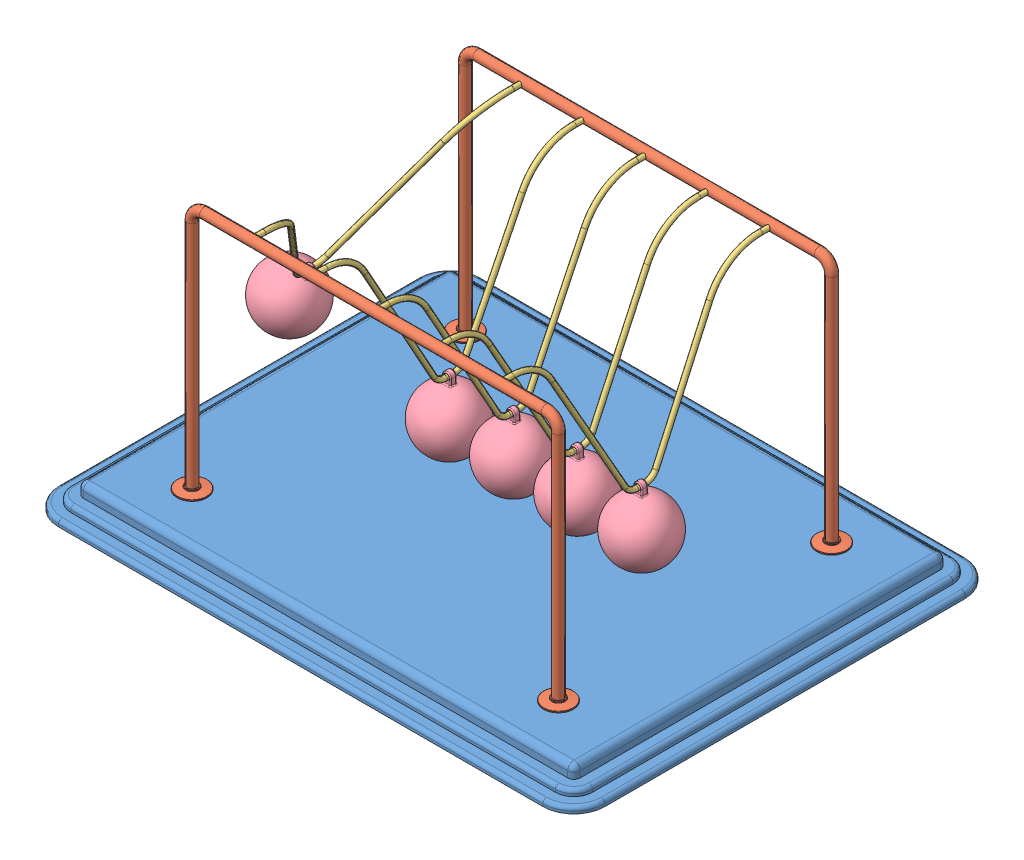
SolidWorks assembly Newtons Cradle NewtonsCradle 0237, configuration Default. Lengths in mm.
Overall size (440 222 340).
13 component instances, 4 part files, 34 mates.
Components (placement in the parent):
- Base NewtonsCradle 0237-1: Base NewtonsCradle 0237 [Default] at (-16.2968 -4.1587 11.425) size (440 20 340)
- frame NewtonsCradle 0237-1: frame NewtonsCradle 0237 [Default] at (-16.2968 144.4547 -98.575) size (319 202 24)
- frame NewtonsCradle 0237-2: frame NewtonsCradle 0237 [Default] at (-16.2968 144.4547 121.425) x (-1 0 0) z (0 0 -1) size (319 202 24)
- Hanging thing NewtonsCradle 0237-1: Hanging thing NewtonsCradle 0237 [Default] at (-157.6326 134.1825 11.425) x (0 0 1) z (-0.859985 0.510319 0) size (220 129 4)
- Hanging thing NewtonsCradle 0237-2: Hanging thing NewtonsCradle 0237 [Default] at (-66.576 122.8418 11.425) x (0 0 1) z (-0.999994 0.003446 0) size (220 129 4)
- Hanging thing NewtonsCradle 0237-3: Hanging thing NewtonsCradle 0237 [Default] at (-15.6923 122.8436 11.425) x (0 0 1) z (-0.999972 -0.007464 0) size (220 129 4)
- Hanging thing NewtonsCradle 0237-4: Hanging thing NewtonsCradle 0237 [Default] at (35.2213 122.8555 11.425) x (0 0 1) z (-0.999824 -0.018742 0) size (220 129 4)
- Hanging thing NewtonsCradle 0237-5: Hanging thing NewtonsCradle 0237 [Default] at (86.0287 122.8747 11.425) x (0 0 1) z (-0.999588 -0.028711 0) size (220 129 4)
- Sphere NewtonsCradle 0237-1: Sphere NewtonsCradle 0237 [Default] at (-195.3962 70.5436 11.425) x (0.859985 -0.510319 0) z (0 0 1) size (50 58.5 50)
- Sphere NewtonsCradle 0237-2: Sphere NewtonsCradle 0237 [Default] at (88.1533 48.9052 11.425) x (0.999588 0.028711 0) z (0 0 1) size (50 58.5 50)
- Sphere NewtonsCradle 0237-3: Sphere NewtonsCradle 0237 [Default] at (-15.14 48.8456 11.425) x (0.999972 0.007464 0) z (0 0 1) size (50 58.5 50)
- Sphere NewtonsCradle 0237-4: Sphere NewtonsCradle 0237 [Default] at (36.6081 48.8685 11.425) x (0.999824 0.018742 0) z (0 0 1) size (50 58.5 50)
- Sphere NewtonsCradle 0237-5: Sphere NewtonsCradle 0237 [Default] at (-66.831 48.8422 11.425) x (0.999994 -0.003446 0) z (0 0 1) size (50 58.5 50)
Mates (geometry in assembly coordinates):
- Coincident1: coincident anti-aligned: plane of Base-1 through (-211.2968 5.8413 156.425) normal (0 1 0); plane of frame-2 through (-175.7968 5.8413 121.425) normal (0 -1 0)
- Coincident2: coincident anti-aligned: plane of Base-1 through (-211.2968 5.8413 156.425) normal (0 1 0); plane of frame-1 through (143.2032 5.8413 -98.575) normal (0 -1 0)
- Concentric1: concentric anti-aligned: cylinder of frame-1 through (-116.2968 203.8413 -94.575) axis (0 0 -1) radius 2; cylinder of frame-2 through (-116.2968 203.8413 117.425) axis (0 0 1) radius 2
- Concentric2: concentric anti-aligned: cylinder of frame-1 through (83.7032 203.8413 -94.575) axis (0 0 -1) radius 2; cylinder of frame-2 through (83.7032 203.8413 117.425) axis (0 0 1) radius 2
- Distance1: distance = 60 mm: plane of frame-1 through (-16.2968 144.4547 -98.575) normal (0 0 1); line of Base-1 through (-211.2968 -12.1587 -158.575) axis (1 0 0)
- Distance2: distance = 60 mm: line of Base-1 through (178.7032 -12.1587 181.425) axis (-1 0 0); plane of frame-2 through (-16.2968 144.4547 121.425) normal (0 0 -1)
- Distance3: distance = 220 mm: plane of frame-2 through (-16.2968 144.4547 121.425) normal (-1 0 0); line of Base-1 through (-236.2968 -12.1587 156.425) axis (0 0 -1)
- Concentric3: concentric anti-aligned: cylinder of frame-1 through (-116.2968 203.8413 -94.575) axis (0 0 -1) radius 2; cylinder of Hanging thing-1 through (-116.2968 203.8413 111.425) axis (0 0 1) radius 2
- Concentric4: concentric anti-aligned: cylinder of frame-1 through (-116.2968 203.8413 -94.575) axis (0 0 -1) radius 2; cylinder of Hanging thing-1 through (-116.2968 203.8413 -98.575) axis (0 0 1) radius 2
- Concentric5: concentric aligned: cylinder of frame-2 through (-66.2968 203.8413 117.425) axis (0 0 1) radius 2; cylinder of Hanging thing-2 through (-66.2968 203.8413 111.425) axis (0 0 1) radius 2
- Concentric6: concentric aligned: cylinder of frame-2 through (-16.2968 203.8413 117.425) axis (0 0 1) radius 2; cylinder of Hanging thing-3 through (-16.2968 203.8413 111.425) axis (0 0 1) radius 2
- Concentric7: concentric aligned: cylinder of frame-2 through (33.7032 203.8413 117.425) axis (0 0 1) radius 2; cylinder of Hanging thing-4 through (33.7032 203.8413 111.425) axis (0 0 1) radius 2
- Concentric8: concentric aligned: cylinder of frame-2 through (83.7032 203.8413 117.425) axis (0 0 1) radius 2; cylinder of Hanging thing-5 through (83.7032 203.8413 111.425) axis (0 0 1) radius 2
- Coincident5: coincident anti-aligned: plane of frame-2 through (83.7032 203.8413 121.425) normal (0 0 -1); plane of Hanging thing-5 through (83.7032 203.8413 121.425) normal (0 0 1)
- Coincident6: coincident anti-aligned: plane of frame-2 through (33.7032 203.8413 121.425) normal (0 0 -1); plane of Hanging thing-4 through (33.7032 203.8413 121.425) normal (0 0 1)
- Coincident7: coincident anti-aligned: plane of frame-2 through (-16.2968 203.8413 121.425) normal (0 0 -1); plane of Hanging thing-3 through (-16.2968 203.8413 121.425) normal (0 0 1)
- Coincident8: coincident anti-aligned: plane of frame-2 through (-66.2968 203.8413 121.425) normal (0 0 -1); plane of Hanging thing-2 through (-66.2968 203.8413 121.425) normal (0 0 1)
- Coincident9: coincident anti-aligned: plane of frame-2 through (-116.2968 203.8413 121.425) normal (0 0 -1); plane of Hanging thing-1 through (-116.2968 203.8413 121.425) normal (0 0 1)
- Concentric9: concentric anti-aligned: cylinder of Hanging thing-1 through (-117.0163 78.8434 7.925) axis (0 0 1) radius 2; cylinder of Sphere-1 through (-117.0163 78.8434 13.925) axis (0 0 -1) radius 2
- Concentric13: concentric anti-aligned: cylinder of Hanging thing-2 through (-66.7276 78.842 7.925) axis (0 0 1) radius 2; cylinder of Sphere-5 through (-66.7276 78.842 13.925) axis (0 0 -1) radius 2
- Concentric15: concentric anti-aligned: cylinder of Hanging thing-3 through (-15.3639 78.8448 7.925) axis (0 0 1) radius 2; cylinder of Sphere-3 through (-15.3639 78.8448 13.925) axis (0 0 -1) radius 2
- Concentric16: concentric anti-aligned: cylinder of Hanging thing-5 through (87.292 78.8928 7.925) axis (0 0 1) radius 2; cylinder of Sphere-2 through (87.292 78.8928 13.925) axis (0 0 -1) radius 2
- Concentric17: concentric anti-aligned: cylinder of Hanging thing-4 through (36.0459 78.8632 7.925) axis (0 0 1) radius 2; cylinder of Sphere-4 through (36.0459 78.8632 13.925) axis (0 0 -1) radius 2
- Parallel1: parallel anti-aligned: plane of Hanging thing-1; plane of Sphere-1
- Coincident22: coincident anti-aligned: plane of Hanging thing-1; plane of Sphere-1
- Coincident12: coincident aligned: plane of Hanging thing-2 through (-66.576 122.8418 11.425) normal (0 0 1); plane of Sphere-5 through (-66.831 48.8422 11.425) normal (0 0 1)
- Coincident10: coincident aligned: plane of Hanging thing-1 through (-116.763 122.8426 11.425) normal (0 0 1); plane of Sphere-1 through (-118.5806 48.8842 11.425) normal (0 0 1)
- Coincident13: coincident anti-aligned: plane of Hanging thing-2 through (-66.576 122.8418 11.425) normal (-0.999994 0.003446 0); plane of Sphere-5 through (-66.831 48.8422 11.425) normal (0.999994 -0.003446 0)
- Coincident14: coincident anti-aligned: plane of Hanging thing-3 through (-15.6923 122.8436 11.425) normal (-0.999972 -0.007464 0); plane of Sphere-3 through (-15.14 48.8456 11.425) normal (0.999972 0.007464 0)
- Coincident15: coincident aligned: plane of Hanging thing-3 through (-15.6923 122.8436 11.425) normal (0 0 1); plane of Sphere-3 through (-15.14 48.8456 11.425) normal (0 0 1)
- Coincident18: coincident aligned: plane of Hanging thing-4 through (35.2213 122.8555 11.425) normal (0 0 1); plane of Sphere-4 through (36.6081 48.8685 11.425) normal (0 0 1)
- Coincident19: coincident anti-aligned: plane of Hanging thing-4 through (35.2213 122.8555 11.425) normal (-0.999824 -0.018742 0); plane of Sphere-4 through (36.6081 48.8685 11.425) normal (0.999824 0.018742 0)
- Coincident20: coincident anti-aligned: plane of Hanging thing-5 through (86.0287 122.8747 11.425) normal (-0.999588 -0.028711 0); plane of Sphere-2 through (88.1533 48.9052 11.425) normal (0.999588 0.028711 0)
- Coincident21: coincident aligned: plane of Hanging thing-5 through (86.0287 122.8747 11.425) normal (0 0 1); plane of Sphere-2 through (88.1533 48.9052 11.425) normal (0 0 1)
